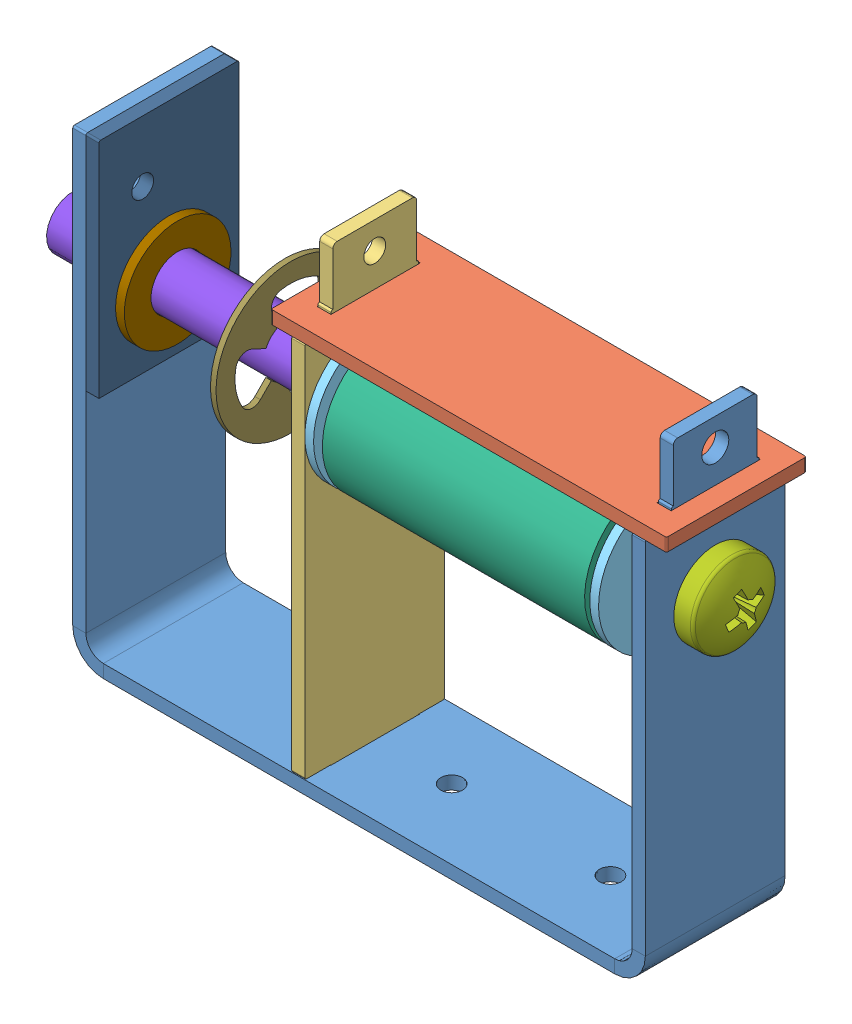
SolidWorks assembly Solenoid Lock, configuration Default. Lengths in mm.
Overall size (77.13 53 22.64).
14 component instances, 13 part files, 33 mates.
Components (placement in the parent):
- Body-1: Body [Default] at (10.0801 0 -26.8976) x (1 0 0) z (0 -1 0) size (65.5 16 53)
- top-1: top [Default] at (32.7522 44.7 -26.8976) x (1 0 0) z (0 -1 0) size (45.25 16 1.5)
- middle wall-1: middle wall [Default] at (36.6301 0.1 -28.8976) x (0 1 0) z (1 0 0) size (52.9 16 1.5)
- plastic pipe-1: plastic pipe [Default] at (36.6801 35.5 -18.8976) x (0 0.036912 -0.999319) z (1 0 0) size (8 8 33.55)
- plastic washer-1: plastic washer [Default] at (69.2301 35.5 -18.8976) x (0 0.938511 0.345251) z (1 0 0) size (16 16 1)
- plastic washer-2: plastic washer [Default] at (36.6301 35.5 -18.8976) x (0 0 -1) z (1 0 0) size (16 16 1)
- winding-1: winding [Default] at (68.6301 35.5 -18.8976) x (0 0.997328 -0.073053) z (-1 0 0) size (16 16 30)
- pan head cross recess screw_iso-1: pan head cross recess screw_iso [ISO 7045 - M5 x 10 - Z - 10N] at (79.2801 35.5 -18.8976) x (-1 0 0) z (0 0.924225 0.381849) size (13.63 9.5 9.5)
- catch-1: catch [Default] at (65.5801 35.5 -18.8976) x (0 -0.635282 0.77228) z (-1 0 0) size (6 6 63.5)
- diy proximity sensor-1: diy proximity sensor [Default] at (50.4301 0 -10.8976) x (-1 0 0) z (0 -1 0) size (24 16 7) (hidden)
- backspring plastic-1: backspring plastic [Default] at (13.0801 35.5 -18.8976) x (0 -0.027844 -0.999612) z (1 0 0) size (12.2 12.2 1)
- catch bush-1: catch bush [Default] at (11.5801 27.5 -26.8976) x (0 -1 0) z (-1 0 0) size (25.5 16 1.5)
- M5 nut-1: M5 nut [Default] at (70.2301 35.5 -18.8976) x (0 1 0) z (1 0 0) size (9.06 7.85 3.85)
- e-external retaining ring_ai-1: e-external retaining ring_ai [B27.1 - NA3-S31] at (26.9801 35.5 -18.8976) x (0 0.708006 -0.706207) z (1 0 0) size (17.02 15 0.64)
Mates (geometry in assembly coordinates):
- Coincident3: coincident anti-aligned: plane of Body-1 through (75.5801 1.5 -10.8976) normal (0 1 0); plane of middle wall-1 through (35.1301 1.5 -11.0976) normal (0 -1 0)
- Coincident4: coincident aligned: plane of Body-1 through (74.0801 3.5 -10.8976) normal (0 0 1); plane of middle wall-1 through (35.1301 1.7 -10.8976) normal (0 0 1)
- Distance1: distance = 0.05 mm anti-aligned: plane of middle wall-1 through (35.1301 44.5 -26.6976) normal (-1 0 0); plane of Body-1 through (35.0801 -8.5 -13.7976) normal (1 0 0)
- Coincident5: coincident anti-aligned: plane of Body-1 through (65.5801 44.7 -10.8976) normal (0 1 0); plane of top-1 through (77.8022 44.7 -11.0976) normal (0 -1 0)
- Distance2: distance = 0.05 mm anti-aligned: plane of top-1 through (74.0301 46.2 -13.7976) normal (1 0 0); plane of Body-1 through (74.0801 50 -10.8976) normal (-1 0 0)
- Distance3: distance = 0.1 mm anti-aligned: plane of Body-1 through (65.5801 46.5 -13.8976) normal (0 0 1); plane of top-1 through (75.6301 46.2 -13.7976) normal (0 0 -1)
- Concentric4: concentric anti-aligned: cylinder of middle wall-1 through (35.1301 35.5 -18.8976) axis (1 0 0) radius 3.025; cylinder of plastic pipe-1 through (70.2301 35.5 -18.8976) axis (-1 0 0) radius 4
- Concentric5: concentric anti-aligned: cylinder of Body-1 through (65.5801 35.5 -18.8976) axis (1 0 0) radius 3; cylinder of plastic washer-1 through (70.2301 35.5 -18.8976) axis (-1 0 0) radius 4
- Coincident8: coincident anti-aligned: plane of M5 nut-1 through (70.2301 35.5 -18.8976) normal (-1 0 0); plane of plastic washer-1 through (70.2301 35.5 -18.8976) normal (1 0 0)
- Coincident9: coincident anti-aligned: plane of M5 nut-1 through (70.2301 35.5 -18.8976) normal (-1 0 0); plane of plastic pipe-1 through (70.2301 35.5 -18.8976) normal (1 0 0)
- Coincident10: coincident anti-aligned: plane of middle wall-1 through (36.6301 44.5 -26.6976) normal (1 0 0); plane of plastic washer-2 through (36.6301 35.5 -18.8976) normal (-1 0 0)
- Concentric6: concentric anti-aligned: cylinder of middle wall-1 through (35.1301 35.5 -18.8976) axis (1 0 0) radius 3.025; cylinder of plastic washer-2 through (37.6301 35.5 -18.8976) axis (-1 0 0) radius 4
- Concentric7: concentric anti-aligned: cylinder of plastic pipe-1 through (70.2301 35.5 -18.8976) axis (-1 0 0) radius 4; cylinder of winding-1 through (38.6301 35.5 -18.8976) axis (1 0 0) radius 8
- Distance4: distance = 1 mm anti-aligned: plane of plastic washer-2 through (37.6301 35.5 -18.8976) normal (1 0 0); plane of winding-1 through (38.6301 35.5 -18.8976) normal (-1 0 0)
- Concentric8: concentric aligned: cylinder of Body-1 through (65.5801 35.5 -18.8976) axis (1 0 0) radius 3; cylinder of pan head cross recess screw_iso-1 through (104.6801 35.5 -18.8976) axis (1 0 0) radius 4.75
- Coincident12: coincident anti-aligned: plane of Body-1 through (75.5801 50 -10.8976) normal (1 0 0); plane of pan head cross recess screw_iso-1 through (75.5801 34.5454 -16.5871) normal (-1 0 0)
- LimitDistance1: limit distance = 10 mm aligned: plane of Body-1 through (75.5801 50 -10.8976) normal (1 0 0); plane of catch-1 through (65.5801 35.5 -18.8976) normal (1 0 0)
- Concentric12: concentric anti-aligned: cylinder of catch-1 through (2.0801 35.5 -18.8976) axis (1 0 0) radius 3; cylinder of backspring plastic-1 through (14.0801 35.5 -18.8976) axis (-1 0 0) radius 3.05
- Concentric13: concentric anti-aligned: cylinder of Body-1 through (45.4301 10 -18.8976) axis (0 -1 0) radius 1.25; cylinder of diy proximity sensor-1 through (45.4301 -7 -18.8976) axis (0 1 0) radius 1.65
- Parallel4: parallel aligned: plane of Body-1 through (10.0801 0 -10.8976) normal (-1 0 0); plane of diy proximity sensor-1 through (30.4301 -7 -10.8976) normal (-1 0 0)
- Coincident15: coincident anti-aligned: plane of Body-1 through (75.5801 0 -10.8976) normal (0 -1 0); plane of diy proximity sensor-1 through (50.4301 0 -10.8976) normal (0 1 0)
- Concentric14: concentric aligned: cylinder of winding-1 through (38.6301 35.5 -18.8976) axis (1 0 0) radius 4; cylinder of catch-1 through (2.0801 35.5 -18.8976) axis (1 0 0) radius 3
- Coincident16: coincident anti-aligned: plane of Body-1 through (11.5801 0 -10.8976) normal (1 0 0); plane of catch bush-1 through (11.5801 52.8 -26.6976) normal (-1 0 0)
- Coincident17: coincident anti-aligned: plane of backspring plastic-1 through (13.0801 35.5 -18.8976) normal (-1 0 0); plane of catch bush-1 through (13.0801 52.8 -26.6976) normal (1 0 0)
- Concentric18: concentric anti-aligned: cylinder of pan head cross recess screw_iso-1 through (104.6801 35.5 -18.8976) axis (1 0 0) radius 2.5; cylinder of M5 nut-1 through (74.0801 35.5 -18.8976) axis (-1 0 0) radius 2.5
- Coincident18: coincident anti-aligned: plane of Body-1 through (74.0801 50 -10.8976) normal (-1 0 0); plane of M5 nut-1 through (74.0801 35.5 -18.8976) normal (1 0 0)
- Concentric20: concentric aligned: cylinder of catch-1 through (2.0801 35.5 -18.8976) axis (1 0 0) radius 3; cylinder of e-external retaining ring_ai-1 through (26.3451 35.5 -18.8976) axis (1 0 0) radius 8.509
- Coincident21: coincident anti-aligned: plane of backspring plastic-1 through (14.0801 12 -18.8976) normal (1 0 0); plane of e-external retaining ring_ai-1 through (14.0801 12 -18.8976) normal (-1 0 0)
- Distance11: distance = 29.265 mm aligned: plane of e-external retaining ring_ai-1 through (26.3451 35.5 -18.8976) normal (-1 0 0); plane of catch-1 through (2.0801 35.5 -18.8976) normal (-1 0 0)
- Parallel5: parallel aligned: plane of Body-1 through (13.5801 3.5 -10.8976) normal (0 0 1); plane of M5 nut-1 through (74.0801 37.7661 -14.9726) normal (0 0 1)
- Lock1: lock: unknown of catch-1; unknown of e-external retaining ring_ai-1
- Concentric21: concentric anti-aligned: cylinder of Body-1 through (1.5801 46 -15.8976) axis (1 0 0) radius 1.5; cylinder of catch bush-1 through (13.0801 46 -15.8976) axis (-1 0 0) radius 1.25
- Concentric22: concentric anti-aligned: cylinder of Body-1 through (1.5801 30.5 -23.8976) axis (1 0 0) radius 1.5; cylinder of catch bush-1 through (13.0801 30.5 -23.8976) axis (-1 0 0) radius 1.25
